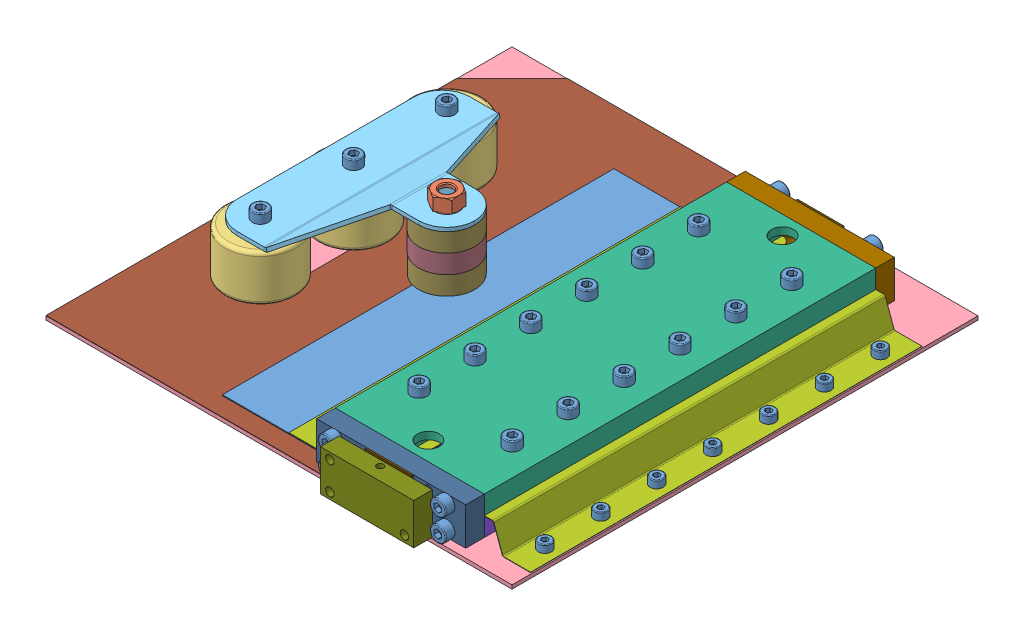
SolidWorks assembly N2 TERP Laser, configuration Standard. Lengths in mm.
Overall size (250 46.81 262.86).
55 component instances, 19 part files, 77 mates.
Components (placement in the parent):
- socket head cap screw_din-8: socket head cap screw_din [DIN 912 M5 x 8 --- 8N] at (-48.5427 12.0114 339.3672) x (0 -1 0) z (0 0 1) size (13 8.5 8.5)
- socket head cap screw_din-9: socket head cap screw_din [DIN 912 M5 x 8 --- 8N] at (-48.5427 12.0114 389.3672) x (0 -1 0) z (0 0 1) size (13 8.5 8.5)
- socket head cap screw_din-10: socket head cap screw_din [DIN 912 M5 x 8 --- 8N] at (-48.5427 12.0114 439.3672) x (0 -1 0) z (0 0 1) size (13 8.5 8.5)
- socket head cap screw_din-12: socket head cap screw_din [DIN 912 M4 x 6 --- 6N] at (154.0973 -16.0986 309.3672) x (0 -1 0) z (0 0 1) size (10 7 7)
- socket head cap screw_din-13: socket head cap screw_din [DIN 912 M4 x 6 --- 6N] at (154.0973 -16.0986 339.3672) x (0 -1 0) z (0 0 1) size (10 7 7)
- socket head cap screw_din-14: socket head cap screw_din [DIN 912 M4 x 6 --- 6N] at (154.0973 -16.0986 369.3672) x (0 -1 0) z (0 0 1) size (10 7 7)
- socket head cap screw_din-15: socket head cap screw_din [DIN 912 M4 x 6 --- 6N] at (154.0973 -16.0986 399.3672) x (0 -1 0) z (0 0 1) size (10 7 7)
- socket head cap screw_din-16: socket head cap screw_din [DIN 912 M4 x 6 --- 6N] at (154.0973 -16.0986 489.3672) x (0 -1 0) z (0.001918 0 0.999998) size (10 7 7)
- socket head cap screw_din-17: socket head cap screw_din [DIN 912 M4 x 6 --- 6N] at (154.0973 -16.0986 459.3672) x (0 -1 0) z (0 0 1) size (10 7 7)
- socket head cap screw_din-18: socket head cap screw_din [DIN 912 M4 x 6 --- 6N] at (154.0973 -16.0986 429.3672) x (0 -1 0) z (0 0 1) size (10 7 7)
- hex nut style 2 gradeab_din-1: hex nut style 2 gradeab_din [Hexagon Nut ISO 4033 - M8 - W - N] at (1.4573 20.7114 389.3672) x (1 0 0) z (0 1 0) size (13 15.01 7.5)
- socket head cap screw_din-19: socket head cap screw_din [DIN 912 M5 x 20 --- 20N] at (126.5966 -12.3032 519.3672) x (0 0 -1) z (1 0.000013 0) size (25 8.5 8.5)
- socket head cap screw_din-20: socket head cap screw_din [DIN 912 M5 x 20 --- 20N] at (126.5966 -0.2032 519.3672) x (0 0 -1) z (0.993685 0.112205 0) size (25 8.5 8.5)
- socket head cap screw_din-21: socket head cap screw_din [DIN 912 M5 x 20 --- 20N] at (66.5966 -0.3032 519.3672) x (0 0 -1) z (1 0.000013 0) size (25 8.5 8.5)
- socket head cap screw_din-22: socket head cap screw_din [DIN 912 M5 x 20 --- 20N] at (66.5966 -12.3032 519.3672) x (0 0 -1) z (1 0.000013 0) size (25 8.5 8.5)
- Doorknob Capacitor 30kV 800pF-1: Doorknob Capacitor 30kV 800pF [Standard] at (-48.5427 -20.9886 439.3672) x (0 1 0) z (-0.999718 0 -0.023728) size (26 38 38)
- Doorknob Capacitor 30kV 800pF-2: Doorknob Capacitor 30kV 800pF [Standard] at (-48.5427 -20.9886 389.3672) x (0 1 0) z (0.519012 0 0.854767) size (26 38 38)
- Doorknob Capacitor 30kV 800pF-3: Doorknob Capacitor 30kV 800pF [Standard] at (-48.5427 -20.9886 339.3672) x (0 1 0) z (-0.982622 0 -0.185617) size (26 38 38)
- Baseplate-1: Baseplate [Standard] at (36.4573 -22.9886 389.3672) x (0 0 -1) z (0 1 0) size (250 250 2)
- Connector Plate-1: Connector Plate [Standard] at (-63.5427 7.0114 451.8672) x (0 0 -1) z (0 1 0) size (125 80 8.2)
- Lasercavity-1: Lasercavity [Standard] at (105.3807 -10.1016 189.3672) size (129.69 29.1 225)
  - Cavity top-2: Cavity top [Standard] at (-8.7841 13.8984 210) x (-1 0 0) z (0 0 1) size (80 10 210)
  - Electrode-1: Electrode [Standard] at (-3.7841 3.8984 315) x (1 0 0) z (0 1 0) size (59.84 210 14.1)
  - Electrode-2: Electrode [Standard] at (-13.7841 3.8984 105) x (-1 0 0) z (0 1 0) size (59.84 210 14.1)
  - Cavity Bottom-2: Cavity Bottom [Standard] at (-8.7841 -6.3016 210) size (80 10 210)
  - socket head cap screw_din-1: socket head cap screw_din [DIN 912 M5 x 20 --- 20N] at (-33.7841 18.8984 285) x (0 -1 0) z (0 0 1) size (25 8.5 8.5)
  - socket head cap screw_din-2: socket head cap screw_din [DIN 912 M5 x 20 --- 20N] at (-33.7841 18.8984 255) x (0 -1 0) z (0 0 1) size (25 8.5 8.5)
  - socket head cap screw_din-3: socket head cap screw_din [DIN 912 M5 x 20 --- 20N] at (-33.7841 18.8984 225) x (0 -1 0) z (0 0 1) size (25 8.5 8.5)
  - socket head cap screw_din-4: socket head cap screw_din [DIN 912 M5 x 20 --- 20N] at (-33.7841 18.8984 195) x (0 -1 0) z (0 0 1) size (25 8.5 8.5)
  - socket head cap screw_din-5: socket head cap screw_din [DIN 912 M5 x 20 --- 20N] at (-33.7841 18.8984 165) x (0 -1 0) z (0 0 1) size (25 8.5 8.5)
  - socket head cap screw_din-6: socket head cap screw_din [DIN 912 M5 x 20 --- 20N] at (-33.7841 18.8984 135) x (0 -1 0) z (0 0 1) size (25 8.5 8.5)
  - socket head cap screw_din-7: socket head cap screw_din [DIN 912 M5 x 20 --- 20N] at (16.2159 18.8984 135) x (0 -1 0) z (0 0 1) size (25 8.5 8.5)
  - socket head cap screw_din-8: socket head cap screw_din [DIN 912 M5 x 20 --- 20N] at (16.2159 18.8984 165) x (0 -1 0) z (0 0 1) size (25 8.5 8.5)
  - socket head cap screw_din-9: socket head cap screw_din [DIN 912 M5 x 20 --- 20N] at (16.2159 18.8984 195) x (0 -1 0) z (0 0 1) size (25 8.5 8.5)
  - socket head cap screw_din-10: socket head cap screw_din [DIN 912 M5 x 20 --- 20N] at (16.2159 18.8984 225) x (0 -1 0) z (0 0 1) size (25 8.5 8.5)
  - socket head cap screw_din-11: socket head cap screw_din [DIN 912 M5 x 20 --- 20N] at (16.2159 18.8984 255) x (0 -1 0) z (0 0 1) size (25 8.5 8.5)
  - socket head cap screw_din-12: socket head cap screw_din [DIN 912 M5 x 20 --- 20N] at (16.2159 18.8984 285) x (0 -1 0) z (0 0 1) size (25 8.5 8.5)
  - socket head cap screw_din-17: socket head cap screw_din [DIN 912 M5 x 20 --- 20N] at (16.2159 9.7984 90) x (0 0 1) z (-1 0 0) size (25 8.5 8.5)
  - socket head cap screw_din-18: socket head cap screw_din [DIN 912 M5 x 20 --- 20N] at (16.2159 -2.2016 90) x (0 0 1) z (-1 0 0) size (25 8.5 8.5)
  - socket head cap screw_din-19: socket head cap screw_din [DIN 912 M5 x 20 --- 20N] at (-33.7841 9.7984 90) x (0 0 1) z (-1 0 0) size (25 8.5 8.5)
  - socket head cap screw_din-20: socket head cap screw_din [DIN 912 M5 x 20 --- 20N] at (-33.7841 -2.2016 90) x (0 0 1) z (-1 0 0) size (25 8.5 8.5)
- Endcap back-1: Endcap back [Standard] at (56.5966 -16.4032 284.3672) size (80 20.2 10)
- Endcap adjustable-1: Endcap adjustable [Standard] at (136.5966 -16.4032 514.3672) x (-1 0 0) z (0 0 -1) size (80 20.2 10)
- Mylar 190um foil-1: Mylar 190um foil [Standard] at (111.4573 -20.9886 514.3672) x (0 0 -1) z (0 1 0) size (250 200 0.19)
- Sparkgap-1: Sparkgap [Standard] at (2.7521 36.2114 391.3592) x (0 0 1) z (0 -1 0) size (39.48 39.48 39)
  - Sparkgapcover-1: Sparkgapcover [Standard] at (-1.992 1.2948 25) size (30 30 10)
  - Sparkgapcenter-1: Sparkgapcenter [Standard] at (-1.992 1.2948 40) size (29.14 30 10)
  - Sparkgapcover-2: Sparkgapcover [Standard] at (-1.992 1.2948 55) x (0.916845 0.399243 0) z (0 0 -1) size (30 30 10)
  - Sparkgap electrode2-1: Sparkgap electrode2 [Standard] at (-1.992 1.2948 17.5) x (0.76076 0.649033 0) z (0 0 1) size (8 8 22)
  - Sparkgap electrode-1: Sparkgap electrode [Standard] at (-1.992 1.2948 56.5) x (0.983227 0.182384 0) z (0 0 -1) size (8 8 15)
- Mirrorholder-1: Mirrorholder [Standard] at (96.5966 -6.3032 517.229) size (50 22 10)
- PFSQ05-03-F01-Solidworks-1: PFSQ05-03-F01-Solidworks [Default] at (96.4966 -6.2032 520.229) x (-1 0 0) z (0 0 -1) size (12.7 12.7 6)
- Microscope slide-1: Microscope slide [Standard] at (96.0966 -6.2032 283.3672) size (25 20 1)
- Microscope slide-2: Microscope slide [Standard] at (96.0966 -6.2032 514.3672) size (25 20 1)
- Secondary Cap plate-1: Secondary Cap plate [Standard] at (21.0961 -20.2986 399.3672) x (1 0 0) z (0 -1 0) size (50 210 0.5)
Mates (geometry in assembly coordinates):
- Deckungsgleich8: coincident anti-aligned: plane of Doorknob Capacitor 30kV 800pF-3 through (-48.5427 -20.9886 339.3672) normal (0 -1 0); plane of Baseplate-1 through (36.4573 -20.9886 389.3672) normal (0 1 0)
- Deckungsgleich9: coincident anti-aligned: plane of Doorknob Capacitor 30kV 800pF-2 through (-48.5427 -20.9886 389.3672) normal (0 -1 0); plane of Baseplate-1 through (36.4573 -20.9886 389.3672) normal (0 1 0)
- Deckungsgleich10: coincident anti-aligned: plane of Doorknob Capacitor 30kV 800pF-1 through (-48.5427 -20.9886 439.3672) normal (0 -1 0); plane of Baseplate-1 through (36.4573 -20.9886 389.3672) normal (0 1 0)
- Konzentrisch5: concentric anti-aligned: cylinder of Doorknob Capacitor 30kV 800pF-1 through (-48.5427 -20.9886 439.3672) axis (0 -1 0) radius 2.1; cylinder of Baseplate-1 through (-48.5427 -22.9886 439.3672) axis (0 1 0) radius 3
- Konzentrisch6: concentric anti-aligned: cylinder of Doorknob Capacitor 30kV 800pF-2 through (-48.5427 -20.9886 389.3672) axis (0 -1 0) radius 2.1; cylinder of Baseplate-1 through (-48.5427 -22.9886 389.3672) axis (0 1 0) radius 3
- Konzentrisch7: concentric anti-aligned: cylinder of Doorknob Capacitor 30kV 800pF-3 through (-48.5427 -20.9886 339.3672) axis (0 -1 0) radius 2.1; cylinder of Baseplate-1 through (-48.5427 -22.9886 339.3672) axis (0 1 0) radius 3
- Konzentrisch8: concentric aligned: cylinder of Doorknob Capacitor 30kV 800pF-3 through (-48.5427 5.0114 339.3672) axis (0 1 0) radius 2.1; cylinder of Connector Plate-1 through (-48.5427 5.0114 339.3672) axis (0 1 0) radius 3
- Konzentrisch9: concentric aligned: cylinder of Doorknob Capacitor 30kV 800pF-1 through (-48.5427 5.0114 439.3672) axis (0 1 0) radius 2.1; cylinder of Connector Plate-1 through (-48.5427 5.0114 439.3672) axis (0 1 0) radius 3
- Deckungsgleich23: coincident aligned: circle of Doorknob Capacitor 30kV 800pF-1; plane of Connector Plate-1 through (-63.5427 5.0114 451.8672) normal (0 -1 0)
- Konzentrisch23: concentric aligned: cylinder of Connector Plate-1 through (-48.5427 5.0114 339.3672) axis (0 1 0) radius 3; cylinder of socket head cap screw_din-8 through (-48.5427 43.7614 339.3672) axis (0 1 0) radius 4.25
- Deckungsgleich41: coincident anti-aligned: plane of Connector Plate-1 through (-63.5427 7.0114 451.8672) normal (0 1 0); plane of socket head cap screw_din-8 through (-44.2927 7.0114 339.3672) normal (0 -1 0)
- Konzentrisch24: concentric aligned: cylinder of Connector Plate-1 through (-48.5427 5.0114 389.3672) axis (0 1 0) radius 3; cylinder of socket head cap screw_din-9 through (-48.5427 43.7614 389.3672) axis (0 1 0) radius 4.25
- Deckungsgleich42: coincident anti-aligned: plane of Connector Plate-1 through (-63.5427 7.0114 451.8672) normal (0 1 0); plane of socket head cap screw_din-9 through (-44.2927 7.0114 389.3672) normal (0 -1 0)
- Konzentrisch25: concentric aligned: cylinder of Connector Plate-1 through (-48.5427 5.0114 439.3672) axis (0 1 0) radius 3; cylinder of socket head cap screw_din-10 through (-48.5427 43.7614 439.3672) axis (0 1 0) radius 4.25
- Deckungsgleich43: coincident anti-aligned: plane of Connector Plate-1 through (-63.5427 7.0114 451.8672) normal (0 1 0); plane of socket head cap screw_din-10 through (-44.2927 7.0114 439.3672) normal (0 -1 0)
- Konzentrisch27: concentric anti-aligned: cylinder of Spark Gap-1/Sparkgap electrode1-1 through (1.4573 -3.6885 389.3672) axis (0 -1 0) radius 4; cylinder of Connector Plate-1 through (1.4573 11.2114 389.3672) axis (0 1 0) radius 4
- Parallel1: parallel aligned: plane of Spark Gap-1/endcap2-1 through (-7.203 2.2214 374.3672) normal (0 0 -1); plane of Connector Plate-1 through (-13.5427 11.2114 374.3672) normal (0 0 -1)
- Konzentrisch28: concentric anti-aligned: cylinder of Spark Gap-1/Sparkgap electrode1-1 through (1.4573 -3.6885 389.3672) axis (0 -1 0) radius 4; cylinder of hex nut gradec_din-1 through (1.4573 18.2114 389.3672) axis (0 1 0) radius 3.4
- Deckungsgleich64: coincident anti-aligned: plane of Connector Plate-1 through (-64.4518 13.2114 451.8672) normal (0 1 0); plane of hex nut gradec_din-1 through (1.4573 18.2114 381.8616) normal (0 -1 0)
- Konzentrisch29: concentric anti-aligned: cylinder of Baseplate-1 through (154.0973 -22.9886 489.3672) axis (0 -1 0) radius 1.65; circle of Lasercavity-1/Elektrode-1
- Konzentrisch30: concentric anti-aligned: cylinder of Baseplate-1 through (154.0973 -22.9886 309.3672) axis (0 -1 0) radius 1.65; circle of Lasercavity-1/Elektrode-1
- Konzentrisch31: concentric aligned: cylinder of Lasercavity-1/Elektrode-1 through (154.0973 -16.2028 309.3672) axis (0 1 0) radius 2.25; cylinder of socket head cap screw_din-12 through (154.0973 19.7472 309.3672) axis (0 1 0) radius 3.5
- Deckungsgleich70: coincident anti-aligned: plane of Lasercavity-1/Elektrode-1 through (101.5238 -16.0028 504.3672) normal (0 1 0); plane of socket head cap screw_din-12 through (157.5973 -16.0028 309.3672) normal (0 -1 0)
- Konzentrisch32: concentric aligned: cylinder of Lasercavity-1/Elektrode-1 through (154.0973 -16.2028 339.3672) axis (0 1 0) radius 2.25; cylinder of socket head cap screw_din-13 through (154.0973 19.7472 339.3672) axis (0 1 0) radius 3.5
- Deckungsgleich71: coincident anti-aligned: plane of Lasercavity-1/Elektrode-1 through (101.5238 -16.0028 504.3672) normal (0 1 0); plane of socket head cap screw_din-13 through (157.5973 -16.0028 339.3672) normal (0 -1 0)
- Konzentrisch33: concentric aligned: cylinder of Lasercavity-1/Elektrode-1 through (154.0973 -16.2028 369.3672) axis (0 1 0) radius 2.25; cylinder of socket head cap screw_din-14 through (154.0973 19.7472 369.3672) axis (0 1 0) radius 3.5
- Deckungsgleich72: coincident anti-aligned: plane of Lasercavity-1/Elektrode-1 through (101.5238 -16.0028 504.3672) normal (0 1 0); plane of socket head cap screw_din-14 through (157.5973 -16.0028 369.3672) normal (0 -1 0)
- Konzentrisch34: concentric aligned: cylinder of Lasercavity-1/Elektrode-1 through (154.0973 -16.2028 399.3672) axis (0 1 0) radius 2.25; cylinder of socket head cap screw_din-15 through (154.0973 19.7472 399.3672) axis (0 1 0) radius 3.5
- Deckungsgleich73: coincident anti-aligned: plane of Lasercavity-1/Elektrode-1 through (101.5238 -16.0028 504.3672) normal (0 1 0); plane of socket head cap screw_din-15 through (157.5973 -16.0028 399.3672) normal (0 -1 0)
- Konzentrisch35: concentric aligned: cylinder of Lasercavity-1/Elektrode-1 through (154.0973 -16.2028 489.3672) axis (0 1 0) radius 2.25; cylinder of socket head cap screw_din-16 through (154.0973 19.7472 489.3672) axis (0 1 0) radius 3.5
- Deckungsgleich74: coincident anti-aligned: plane of Lasercavity-1/Elektrode-1 through (101.5238 -16.0028 504.3672) normal (0 1 0); plane of socket head cap screw_din-16 through (157.5973 -16.0028 489.3605) normal (0 -1 0)
- Konzentrisch36: concentric aligned: cylinder of Lasercavity-1/Elektrode-1 through (154.0973 -16.2028 459.3672) axis (0 1 0) radius 2.25; cylinder of socket head cap screw_din-17 through (154.0973 19.7472 459.3672) axis (0 1 0) radius 3.5
- Deckungsgleich75: coincident anti-aligned: plane of Lasercavity-1/Elektrode-1 through (101.5238 -16.0028 504.3672) normal (0 1 0); plane of socket head cap screw_din-17 through (157.5973 -16.0028 459.3672) normal (0 -1 0)
- Konzentrisch37: concentric aligned: cylinder of Lasercavity-1/Elektrode-1 through (154.0973 -16.2028 429.3672) axis (0 1 0) radius 2.25; cylinder of socket head cap screw_din-18 through (154.0973 19.7472 429.3672) axis (0 1 0) radius 3.5
- Deckungsgleich76: coincident anti-aligned: plane of Lasercavity-1/Elektrode-1 through (101.5238 -16.0028 504.3672) normal (0 1 0); plane of socket head cap screw_din-18 through (157.5973 -16.0028 429.3672) normal (0 -1 0)
- Abstand1: distance = 10 mm anti-aligned: plane of Cap plate-1 through (41.7519 -20.9886 504.3672) normal (1 0 0); plane of Lasercavity-1/Electrode-2 through (31.7519 -20.9886 294.3672) normal (-1 0 0)
- Deckungsgleich79: coincident aligned: plane of Lasercavity-1/Electrode-2 through (46.6118 -20.9886 294.3672) normal (0 0 -1); plane of Cap plate-1 through (41.7519 -20.9886 294.3672) normal (0 0 -1)
- Deckungsgleich80: coincident: point of Lasercavity-1/Electrode-2; plane of Cap plate-1 through (16.7519 -20.4886 399.3672) normal (0 1 0)
- Konzentrisch38: concentric aligned: cylinder of Lasercavity-1/socket head cap screw_din-17 through (121.5966 3.7925 247.6172) axis (0 0 -1) radius 2.5; cylinder of Endcap back-1 through (121.5966 3.7925 294.3672) axis (0 0 -1) radius 2.65
- Deckungsgleich81: coincident anti-aligned: plane of Lasercavity-1/Gehäuse-2 through (96.5966 7.8925 294.3672) normal (0 0 -1); plane of Endcap back-1 through (56.5966 -12.3075 294.3672) normal (0 0 1)
- Deckungsgleich83: coincident anti-aligned: plane of Baseplate-1 through (36.4573 -20.9886 389.3672) normal (0 1 0); plane of Cap plate-1 through (16.7519 -20.9886 399.3672) normal (0 -1 0)
- Konzentrisch39: concentric aligned: cylinder of Lasercavity-1/socket head cap screw_din-20 through (71.5966 -8.2075 247.6172) axis (0 0 -1) radius 2.5; cylinder of Endcap back-1 through (71.5966 -8.2075 294.3672) axis (0 0 -1) radius 2.65
- Deckungsgleich85: coincident anti-aligned: plane of Baseplate-1 through (36.4573 -20.9886 389.3672) normal (0 1 0); plane of Mylar 190um foil-1 through (111.4573 -20.9886 514.3672) normal (0 -1 0)
- Deckungsgleich86: coincident aligned: plane of Baseplate-1 through (161.4573 -20.9886 264.3672) normal (0 0 -1); plane of Mylar 190um foil-1 through (111.4573 -20.7986 264.3672) normal (0 0 -1)
- Konzentrisch42: concentric aligned: cylinder of Connector Plate-1 through (1.4573 11.2114 389.3672) axis (0 1 0) radius 4; cylinder of Sparkgap-1/Sparkgap electrode2-1 through (1.4573 -3.2886 389.3672) axis (0 1 0) radius 4
- Deckungsgleich88: coincident anti-aligned: plane of Connector Plate-1 through (-64.4518 11.2114 451.8672) normal (0 -1 0); plane of Sparkgap-1/Sparkgapcover-1 through (1.4573 11.2114 389.3672) normal (0 1 0)
- Konzentrisch43: concentric aligned: cylinder of Connector Plate-1 through (1.4573 11.2114 389.3672) axis (0 1 0) radius 4; cylinder of hex nut style 2 gradeab_din-1 through (1.4573 -4.3261 389.3672) axis (0 1 0) radius 4
- Deckungsgleich89: coincident anti-aligned: plane of Connector Plate-1 through (-64.4518 13.2114 451.8672) normal (0 1 0); plane of hex nut style 2 gradeab_din-1 through (1.4573 13.2114 381.8616) normal (0 -1 0)
- Parallel2: parallel aligned: plane of Baseplate-1 through (161.4573 -20.9886 264.3672) normal (0 0 -1); plane of Sparkgap-1/Sparkgapcenter-1 through (-3.5427 1.2114 375.2251) normal (0 0 -1)
- Konzentrisch48: concentric aligned: cylinder of Lasercavity-1/Gehäuse-2 through (126.5966 3.8925 504.3672) axis (0 0 1) radius 2.1; cylinder of socket head cap screw_din-20 through (126.5966 3.8925 551.1172) axis (0 0 1) radius 2.5
- Deckungsgleich95: coincident aligned: plane of Baseplate-1 through (-88.5427 -20.9886 514.3672) normal (-1 0 0); plane of Mylar 190um foil-1 through (-88.5427 -20.7986 514.3672) normal (-1 0 0)
- Deckungsgleich96: coincident: unknown of Lasercavity-1/Gehäuse-2; unknown of Endcap adjustable-1
- Deckungsgleich97: coincident: unknown of Lasercavity-1/Gehäuse-2; unknown of Endcap adjustable-1
- Deckungsgleich98: coincident: unknown of Lasercavity-1/Gehäuse unten-2; unknown of Endcap adjustable-1
- Konzentrisch49: concentric aligned: cylinder of Endcap adjustable-1 through (66.5966 3.7925 504.3672) axis (0 0 1) radius 2.65; cylinder of socket head cap screw_din-21 through (66.5966 3.7925 551.1172) axis (0 0 1) radius 2.5
- Deckungsgleich99: coincident aligned: plane of Endcap adjustable-1 through (136.5966 -12.3075 514.3672) normal (0 0 1); circle of socket head cap screw_din-21
- Konzentrisch50: concentric aligned: cylinder of Endcap adjustable-1 through (66.5966 -8.2075 504.3672) axis (0 0 1) radius 2.65; cylinder of socket head cap screw_din-22 through (66.5966 -8.2075 551.1172) axis (0 0 1) radius 2.5
- Deckungsgleich100: coincident aligned: plane of Endcap adjustable-1 through (136.5966 -12.3075 514.3672) normal (0 0 1); circle of socket head cap screw_din-22
- Deckungsgleich101: coincident aligned: plane of Endcap adjustable-1 through (136.5966 -12.3075 514.3672) normal (0 0 1); circle of socket head cap screw_din-20
- Konzentrisch51: concentric aligned: cylinder of Endcap adjustable-1 through (126.5966 -8.2075 504.3672) axis (0 0 1) radius 2.65; cylinder of socket head cap screw_din-19 through (126.5966 -8.2075 551.1172) axis (0 0 1) radius 2.5
- Deckungsgleich102: coincident aligned: plane of Endcap adjustable-1 through (136.5966 -12.3075 514.3672) normal (0 0 1); circle of socket head cap screw_din-19
- Deckungsgleich103: coincident: line of Mirrorholder-1 through (92.1466 4.2425 517.229) axis (1 0 0); plane of PFSQ05-03-F01-Solidworks-1 through (90.1466 4.2425 517.229) normal (0 1 0)
- Deckungsgleich104: coincident: line of Mirrorholder-1 through (90.1466 -6.6575 523.229) axis (0 1 0); plane of PFSQ05-03-F01-Solidworks-1 through (90.1466 4.2425 517.229) normal (-1 0 0)
- Deckungsgleich105: coincident anti-aligned: plane of Mirrorholder-1 through (96.5966 -2.2075 523.229) normal (0 0 -1); plane of PFSQ05-03-F01-Solidworks-1 through (102.8466 4.2425 523.229) normal (0 0 1)
- Deckungsgleich106: coincident anti-aligned: plane of Endcap back-1 through (56.5966 -12.3075 284.3672) normal (0 0 -1); plane of Microscope slide-1 through (96.0966 -2.1075 284.3672) normal (0 0 1)
- Deckungsgleich107: coincident aligned: plane of Endcap back-1 through (56.5966 7.8925 294.3672) normal (0 1 0); plane of Microscope slide-1 through (108.5966 7.8925 284.3672) normal (0 1 0)
- Abstand2: distance = 28 mm aligned: plane of Microscope slide-1 through (108.5966 -16.2032 284.3672) normal (1 0 0); plane of Endcap back-1 through (136.5966 -16.4032 294.3672) normal (1 0 0)
- Deckungsgleich108: coincident aligned: plane of Microscope slide-1 through (83.5966 -12.1075 284.3672) normal (-1 0 0); plane of Microscope slide-2 through (83.5966 -12.1075 515.3672) normal (-1 0 0)
- Deckungsgleich109: coincident aligned: plane of Endcap adjustable-1 through (136.5966 7.8925 504.3672) normal (0 1 0); plane of Microscope slide-2 through (108.5966 7.8925 515.3672) normal (0 1 0)
- Deckungsgleich110: coincident: plane of Endcap adjustable-1 through (136.5966 -12.3075 514.3672) normal (0 0 1); line of Microscope slide-2 through (83.5966 7.8925 514.3672) axis (0 -1 0)
- Konzentrisch52: concentric anti-aligned: cylinder of Endcap adjustable-1 through (76.5966 -9.7075 504.3672) axis (0 0 -1) radius 1.85; cylinder of Mirrorholder-1 through (76.5966 -9.7075 517.229) axis (0 0 1) radius 2.25
- Konzentrisch53: concentric anti-aligned: cylinder of Endcap adjustable-1 through (116.5966 -9.7075 504.3672) axis (0 0 -1) radius 1.85; cylinder of Mirrorholder-1 through (116.5966 -9.7075 517.229) axis (0 0 1) radius 2.25
- Abstand3: distance = 3 mm: line of Mirrorholder-1 through (71.5966 -17.3032 517.229) axis (1 0 0); line of Endcap adjustable-1 through (136.5966 -16.4032 514.3672) axis (-1 0 0)
- Deckungsgleich111: coincident: plane of Mylar 190um foil-1 through (111.4573 -20.7986 514.3672) normal (0 1 0); plane of Secondary Cap plate-1 through (19.2502 -20.7986 399.3672) normal (0 -1 0)
- Deckungsgleich112: coincident: plane of Lasercavity-1/Electrode-2 through (46.539 -20.2986 294.3672) normal (0 0 -1); plane of Secondary Cap plate-1 through (-5.7498 -20.7986 294.3672) normal (0 0 -1)
- Deckungsgleich113: coincident: plane of Lasercavity-1/Electrode-2 through (91.6693 -20.2986 294.3672) normal (0 -1 0); plane of Secondary Cap plate-1 through (21.0961 -20.2986 399.3672) normal (0 1 0)
- Deckungsgleich114: coincident: plane of Lasercavity-1/Electrode-2; plane of Secondary Cap plate-1 through (46.0961 -20.7986 504.3672) normal (1 0 0)
